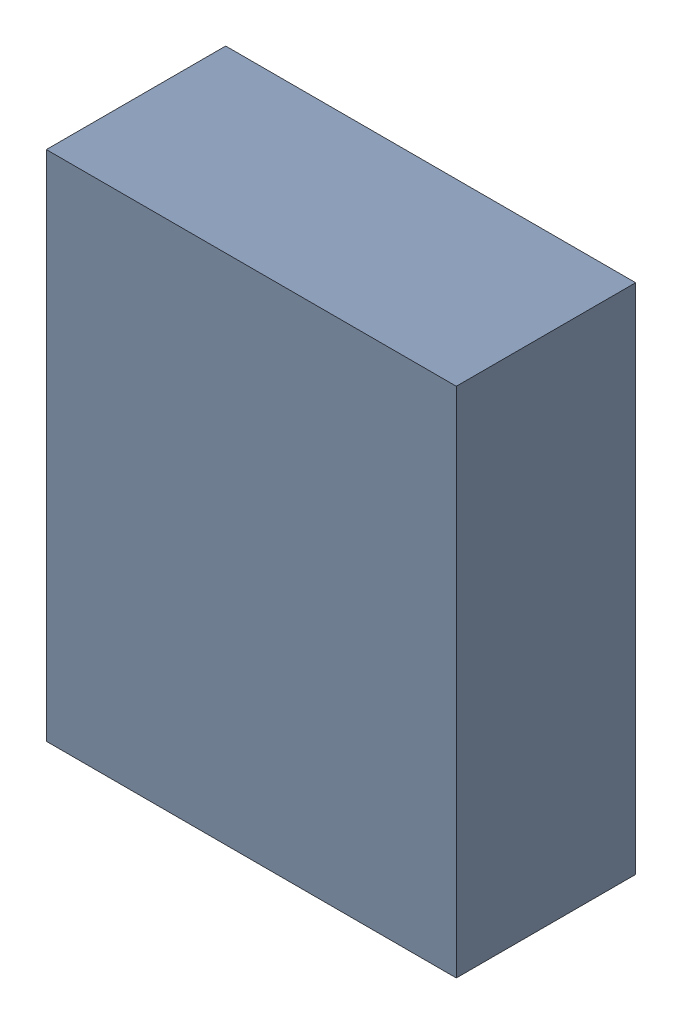
SolidWorks assembly Q1, configuration Default. Lengths in mm.
Overall size (4 5 1.75).
2 component instances, 1 part files, 0 mates.
Components (placement in the parent):
- 1540840904-1: 1540840904 [Default] at (16.75 -16.5 -2.1615) size (4 5 1.75)
  - Extruded_3-1: Extruded_3 [Default] at origin size (4 5 1.75)
